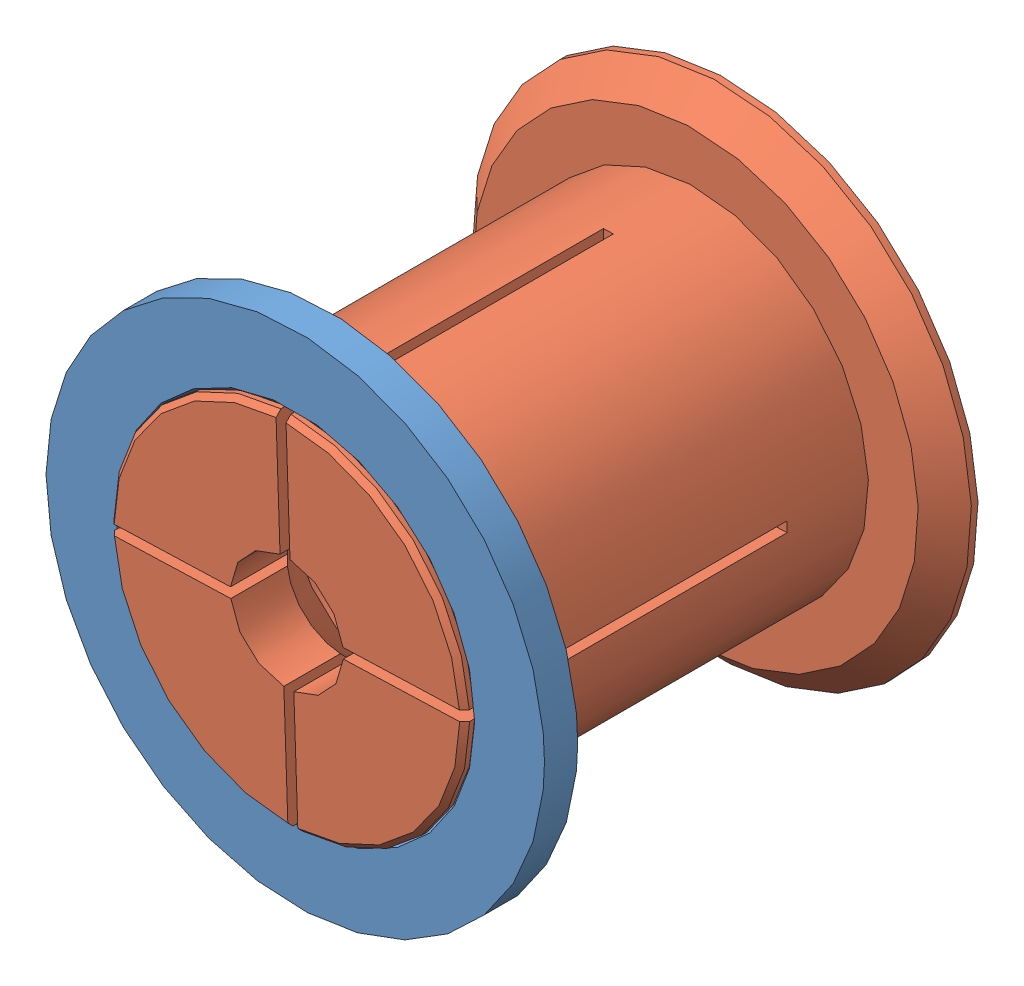
SolidWorks assembly 53-55-17-spool-adapter, configuration Default. Lengths in mm.
Overall size (77.51 77.51 66.5).
2 component instances, 2 part files, 2 mates.
Components (placement in the parent):
- 53-55-17-spool-adapter-female-1: 53-55-17-spool-adapter-female [Default] at (4.7434 31.7057 72.3889) size (75 75 5)
- 53-55-17-spool-adapter-male-1: 53-55-17-spool-adapter-male [Default] at (4.7434 31.7057 17.1389) x (0.999421 0.034015 0) z (0 0 1) size (75 75 66.5)
Mates (geometry in assembly coordinates):
- Concentric1: concentric: cylinder of 53-55-17-spool-adapter-female-1 through (4.7434 31.7057 72.3889) axis (0 0 1) radius 26.25; cylinder of 53-55-17-spool-adapter-male-1 through (4.7434 31.7057 78.6389) axis (0 0 -1) radius 26
- Coincident1: coincident aligned: cone of 53-55-17-spool-adapter-female-1 through (4.7434 31.7057 77.3889) axis (0 0 -1); cone of 53-55-17-spool-adapter-male-1 through (4.7434 31.7057 77.1389) axis (0 0 -1)
